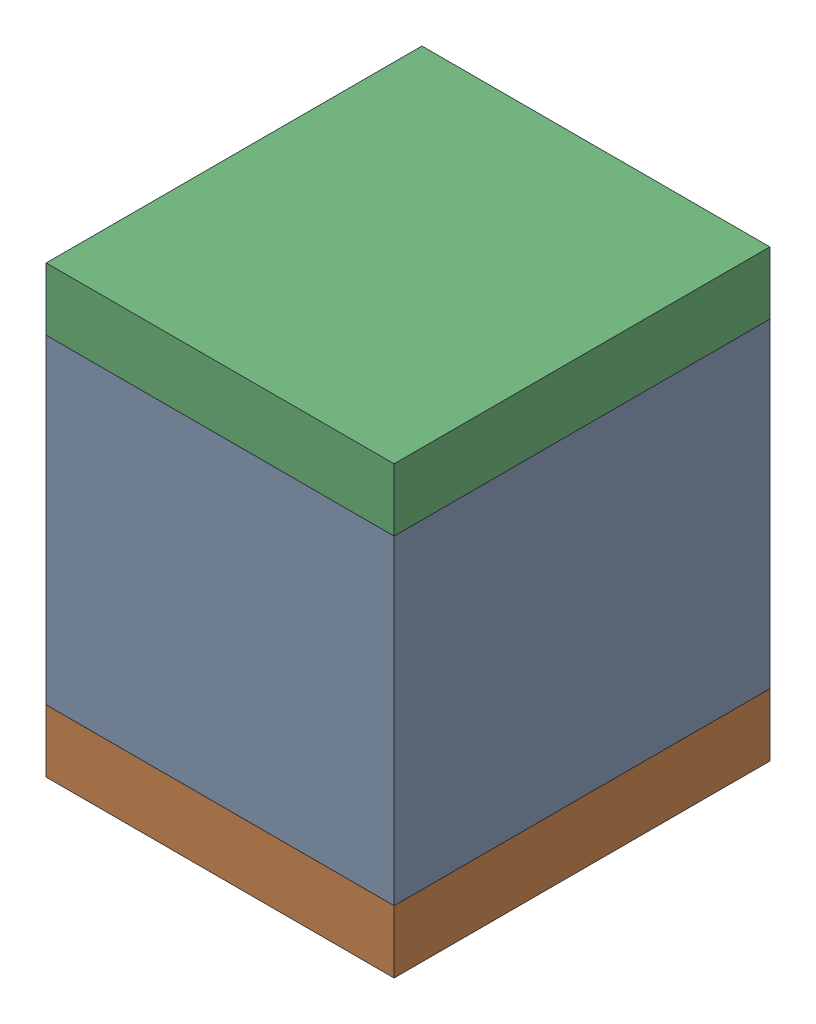
SolidWorks assembly C14, configuration ﾃﾞﾌｫﾙﾄ. Lengths in mm.
Overall size (2.5 3.2 2.7).
6 component instances, 2 part files, 0 mates.
Components (placement in the parent):
- 689260016-1: 689260016 [ﾃﾞﾌｫﾙﾄ] at (77.25 57.75 0) size (2.5 2.3 2.7)
  - Extruded_6-1: Extruded_6 [ﾃﾞﾌｫﾙﾄ] at origin size (2.5 2.3 2.7)
- 689260152-1: 689260152 [ﾃﾞﾌｫﾙﾄ] at (77.2501 56.375 0) size (2.5 0.45 2.7)
  - Extruded_7-1: Extruded_7 [ﾃﾞﾌｫﾙﾄ] at origin size (2.5 0.45 2.7)
- 689260152-2: 689260152 [ﾃﾞﾌｫﾙﾄ] at (77.2501 59.125 0) size (2.5 0.45 2.7)
  - Extruded_7-1: Extruded_7 [ﾃﾞﾌｫﾙﾄ] at origin size (2.5 0.45 2.7)
